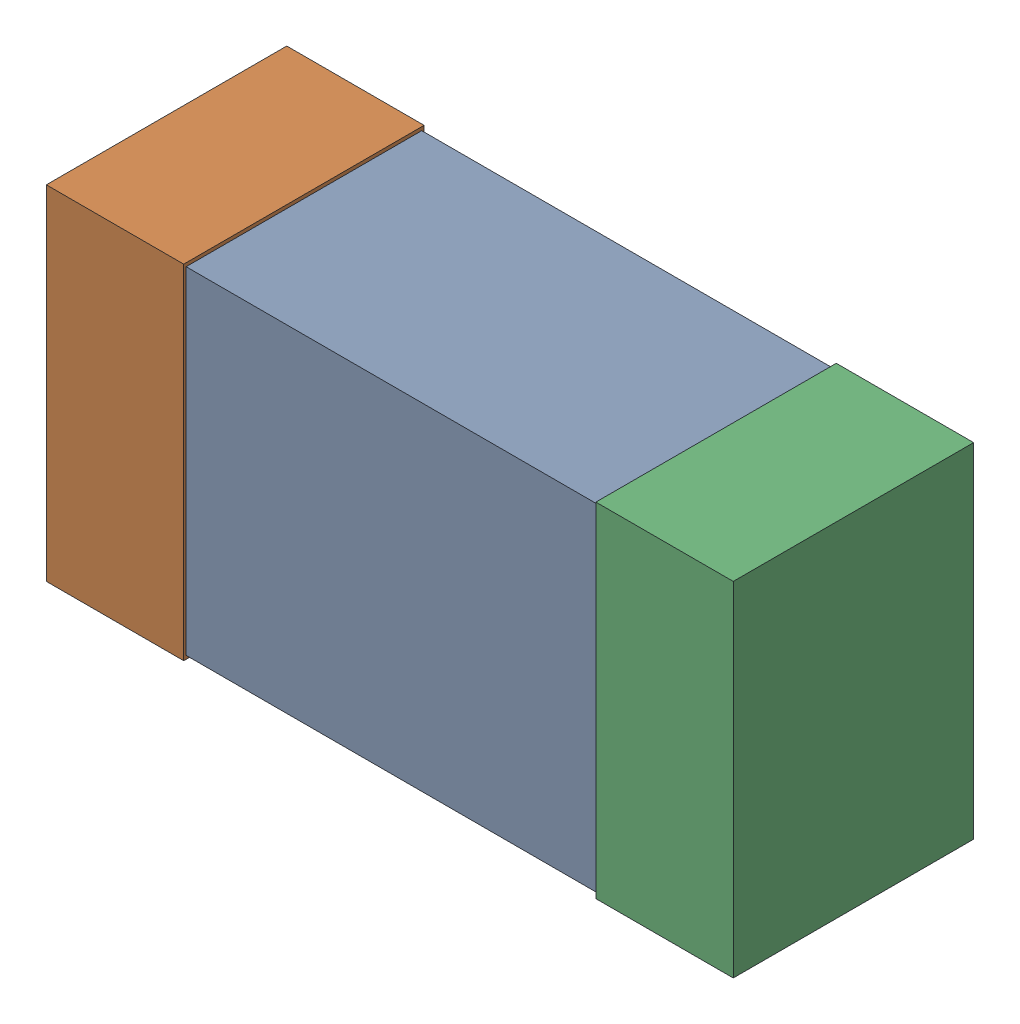
SolidWorks assembly R4, configuration Predeterminado. Lengths in mm.
Overall size (1 0.5 0.35).
4 component instances, 3 part files, 0 mates.
Components (placement in the parent):
- 6074689680-1: 6074689680 [Predeterminado] at (27.5 41.5 0) x (-1 0 0) z (0 0 1) size (1 0.5 0.35)
  - body-2-1: body-2 [Predeterminado] at (-0.3 -0.245 0.0035) size (0.6 0.49 0.34)
  - term2-1-1: term2-1 [Predeterminado] at (0.3 -0.25 0) size (0.2 0.5 0.35)
  - term1-1-1: term1-1 [Predeterminado] at (-0.5 -0.25 0) size (0.2 0.5 0.35)
